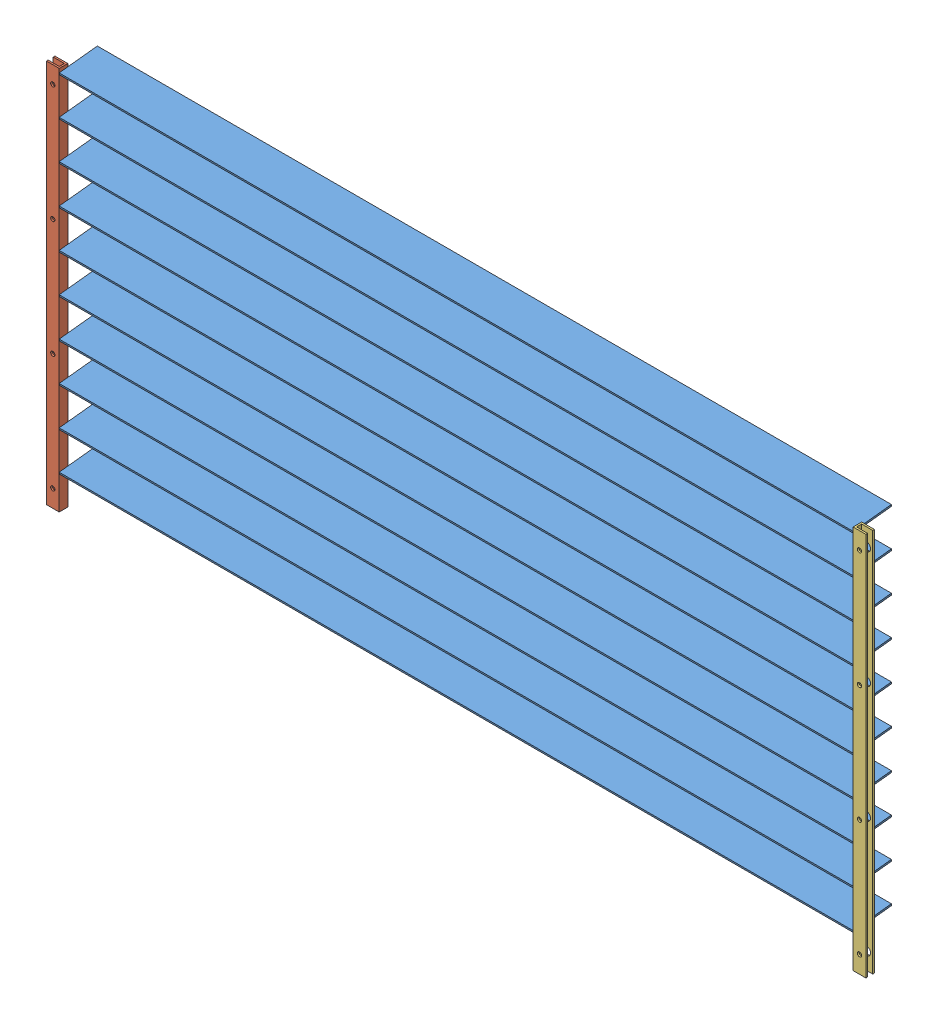
SolidWorks assembly Radiation Covering, configuration Default. Lengths in mm.
Overall size (1219.2 571.99 57.27).
12 component instances, 3 part files, 6 mates.
Components (placement in the parent):
- Strip-1: Strip [Default] at (518.1262 574.6482 448.9051) x (1 0 0) z (0 -0.993946 -0.109873) size (1206.5 57.15 2.54)
- Holding Bar-3: Holding Bar [Default] at (-72.4238 292.8063 470.9955) size (19.05 571.5 12.7)
- Holding Bar Right-1: Holding Bar Right [Default] at (1108.6762 292.8063 471.2819) size (19.05 571.5 12.7)
- Strip-2: Strip [Default] at (518.1262 517.4982 448.9051) x (1 0 0) z (0 -0.993946 -0.109873) size (1206.5 57.15 2.54)
- Strip-3: Strip [Default] at (518.1262 460.3482 448.9051) x (1 0 0) z (0 -0.993946 -0.109873) size (1206.5 57.15 2.54)
- Strip-4: Strip [Default] at (518.1262 403.1982 448.9051) x (1 0 0) z (0 -0.993946 -0.109873) size (1206.5 57.15 2.54)
- Strip-5: Strip [Default] at (518.1262 346.0482 448.9051) x (1 0 0) z (0 -0.993946 -0.109873) size (1206.5 57.15 2.54)
- Strip-6: Strip [Default] at (518.1262 288.8982 448.9051) x (1 0 0) z (0 -0.993946 -0.109873) size (1206.5 57.15 2.54)
- Strip-7: Strip [Default] at (518.1262 231.7482 448.9051) x (1 0 0) z (0 -0.993946 -0.109873) size (1206.5 57.15 2.54)
- Strip-8: Strip [Default] at (518.1262 174.5982 448.9051) x (1 0 0) z (0 -0.993946 -0.109873) size (1206.5 57.15 2.54)
- Strip-9: Strip [Default] at (518.1262 117.4482 448.9051) x (1 0 0) z (0 -0.993946 -0.109873) size (1206.5 57.15 2.54)
- Strip-10: Strip [Default] at (518.1262 60.2982 448.9051) x (1 0 0) z (0 -0.993946 -0.109873) size (1206.5 57.15 2.54)
Mates (geometry in assembly coordinates):
- Concentric3: concentric aligned: cylinder of Strip-1 through (1137.6683 572.2063 470.9955) axis (-1 0 0) radius 1.27; cylinder of Holding Bar Right-1 through (1127.7262 572.2063 470.9955) axis (-1 0 0) radius 1.27
- Coincident2: coincident anti-aligned: plane of Strip-1 through (1108.6762 576.5255 420.3635) normal (1 0 0); plane of Holding Bar Right-1 through (1108.6762 578.5563 477.6319) normal (-1 0 0)
- Concentric4: concentric anti-aligned: cylinder of Strip-1 through (1137.6683 572.2063 470.9955) axis (-1 0 0) radius 1.27; cylinder of Holding Bar-3 through (-91.4738 572.2063 470.9955) axis (1 0 0) radius 1.27
- Coincident3: coincident anti-aligned: plane of Strip-1 through (-72.4238 576.5255 420.3635) normal (-1 0 0); plane of Holding Bar-3 through (-72.4238 578.5563 477.3455) normal (1 0 0)
- Parallel1: parallel aligned: plane of Holding Bar-3 through (-72.4238 578.5563 477.3455) normal (0 0 1); plane of Holding Bar Right-1 through (1108.6762 578.5563 477.6319) normal (0 0 1)
- LimitAngle1: limit planar angle = 1.680891 rad aligned: plane of Strip-1 through (518.1262 575.9105 449.0446) normal (0 0.993946 0.109873); plane of Holding Bar Right-1 through (1108.6762 578.5563 464.9319) normal (0 0 -1)
